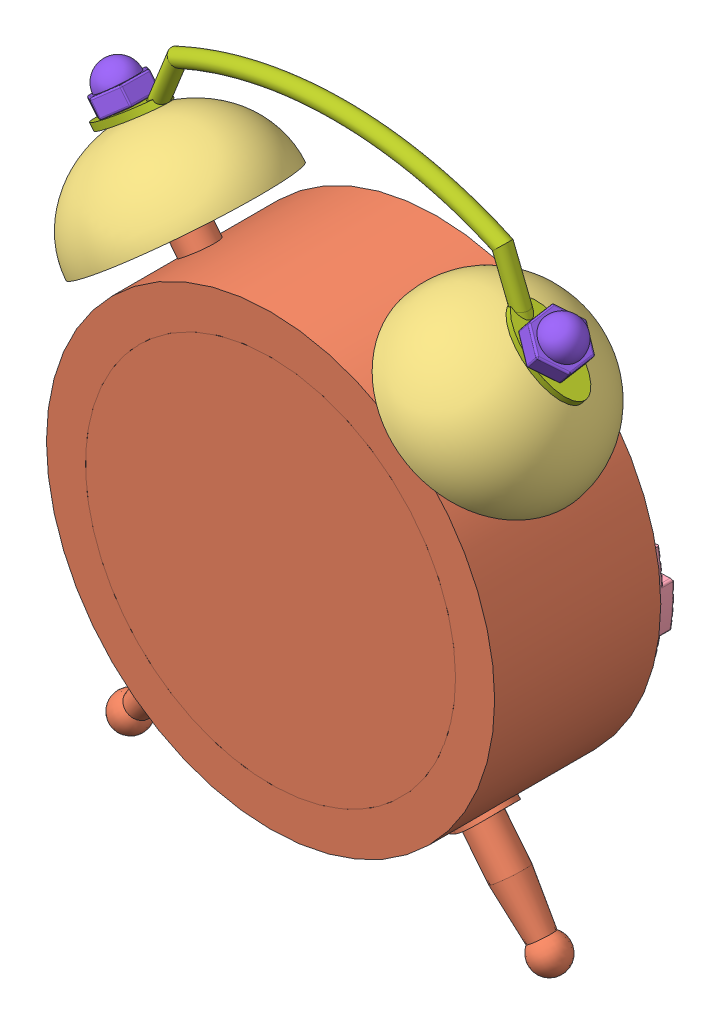
SolidWorks assembly m&m clock assembly, configuration Default. Lengths in mm.
Overall size (94.51 74.03 40.11).
13 component instances, 9 part files, 25 mates.
Components (placement in the parent):
- inner body-1: inner body [Default] at origin size (49.9 49.9 19.3)
- clock casing-2: clock casing [Default] at (0 0 18.3) size (94.51 65.37 40.11)
- bell-1: bell [Default] at (17.3435 21.8712 10.4494) x (0.780381 -0.625305 0) z (0 0 1) size (21.5 9.58 21.5)
- bell-2: bell [Default] at (-17.5711 21.6888 10.4) x (0.780381 0.625305 0) z (0 0 1) size (21.5 9.58 21.5)
- alarm switch-2: alarm switch [Default] x (-0.998274 0.058723 0) z (0 0 -1) size (25.97 12.5 2.77)
- battery lid-1: battery lid [Default] at (-6.5 -13.95 1.5) x (-0.971009 0.239044 0) z (-0.239044 -0.971009 0) size (13 3 13)
- dials-1: dials [Default] at (12.533 -11.5461 0) x (0.996737 0.08072 0) z (-0.08072 0.996737 0) size (7.02 1.74 7.02)
- dials-2: dials [Default] at (-11.5 8.45 0) x (1 0 0) z (0 1 0) size (7.02 1.74 7.02)
- bell bar-5: bell bar [Default] at (0.01 32.3835 10.4) x (1 0.00008 0) z (0 0 1) size (56.5 17.19 4.8)
- bell nut-2: bell nut [Default] at (24.0117 29.9666 10.4) x (0.767462 -0.614953 -0.181205) z (0.141409 -0.113308 0.983445) size (5.59 5.44 6.16)
- bell nut-3: bell nut [Default] at (-24.0117 29.9666 10.4) x (0.780381 0.625305 0) z (0 0 1) size (5.59 5.44 6.16)
- screw-2: screw [Default] at (0 22.2891 -0.0044) x (-0.954512 0.298172 0) z (-0.298172 -0.954512 0) size (3 6.5 3)
- screw-3: screw [Default] at (0 -22.2891 -0.1074) x (-0.999748 -0.022436 0) z (0.022436 -0.999748 0) size (3 6.5 3)
Mates (geometry in assembly coordinates):
- Coincident4: coincident anti-aligned: plane of clock face + plastic-1 through (0 0 17.8) normal (0 0 1); plane of main body-2 through (0 0 17.8) normal (0 0 -1)
- Concentric2: concentric aligned: cylinder of clock face + plastic-1 through (0 0 17.8) axis (0 0 -1) radius 24.95; cylinder of main body-2 through (0 0 17.8) axis (0 0 -1) radius 25
- Tangent1: tangent: cylinder of assembly; face of clock casing-2; cylinder of bell-1 through (17.3435 21.8712 10.4494) axis (0.625305 0.780381 0) radius 1.6
- Coincident6: coincident anti-aligned: plane of main body-2 through (23.1363 28.8741 10.4) normal (0.625305 0.780381 0); circle of bell-1
- Tangent2: tangent: cylinder of assembly; face of clock casing-2; cylinder of bell-2 through (-17.5711 21.6888 10.4) axis (-0.625305 0.780381 0) radius 1.6
- Coincident7: coincident anti-aligned: plane of main body-2 through (-23.1363 28.8741 10.4) normal (-0.625305 0.780381 0); circle of bell-2
- Coincident9: coincident anti-aligned: plane of clock face + plastic-1 through (0 0 0) normal (0 0 -1); plane of alarm switch-2 through (0 0 0) normal (0 0 1)
- Concentric7: concentric aligned: cylinder of clock face + plastic-1 through (0 0 -1) axis (0 0 1) radius 0.5; cylinder of alarm switch-2 through (0 0 -1) axis (0 0 1) radius 0.5
- Coincident10: coincident anti-aligned: plane of clock face + plastic-1 through (-6.5 -13.95 1.5) normal (0 0 -1); plane of battery lid-1 through (-6.5 -13.95 1.5) normal (0 0 1)
- Coincident11: coincident aligned: circle of clock face + plastic-1; circle of battery lid-1
- Concentric8: concentric aligned: cylinder of clock face + plastic-1 through (12.533 -11.5461 -1) axis (0 0 1) radius 0.5; cylinder of dials-1 through (12.533 -11.5461 -1) axis (0 0 1) radius 0.5
- Coincident15: coincident aligned: plane of clock face + plastic-1 through (0 0 0) normal (0 0 -1); circle of dials-1
- Concentric9: concentric aligned: cylinder of clock face + plastic-1 through (-11.5 8.45 -1) axis (0 0 1) radius 0.5; cylinder of dials-2 through (-11.5 8.45 -1) axis (0 0 1) radius 0.5
- Coincident16: coincident aligned: plane of clock face + plastic-1 through (0 0 0) normal (0 0 -1); circle of dials-2
- Concentric18: concentric aligned: circle of main body-2; circle of bell bar (1)-5
- Coincident22: coincident aligned: circle of bell-2; plane of bell bar (1)-5 through (-23.4419 29.2554 10.4) normal (0.625305 -0.780381 0)
- Parallel1: parallel: plane of main body-2 through (0 0 10.4) normal (0 0 1); line of bell bar (1)-5 through (-24.755 32.3815 10.4) axis (1 0.00008 0)
- Concentric22: concentric aligned: circle of main body-2; circle of bell nut+bolt-2
- Distance2: distance = 0.1 mm anti-aligned: plane of main body-2 through (26.2628 32.776 10.4) normal (0.625305 0.780381 0); plane of bell nut+bolt-2 through (26.3253 32.854 10.4) normal (-0.625305 -0.780381 0)
- Concentric24: concentric anti-aligned: circle of main body-2; circle of bell nut+bolt-3
- Distance3: distance = 0.1 mm anti-aligned: plane of bell nut+bolt-3 through (-26.3253 32.854 10.4) normal (0.625305 -0.780381 0); plane of main body-2 through (-26.2628 32.776 10.4) normal (-0.625305 0.780381 0)
- Parallel4: parallel: line of main body-2 through (-45.6453 -31.2 10.4) axis (1 0 0)
- Perpendicular2: perpendicular: line of main body-2 through (-45.6453 -31.2 10.4) axis (1 0 0)
- Concentric25: concentric aligned: circle of clock face + plastic-1; circle of screw-2
- Concentric26: concentric aligned: circle of clock face + plastic-1; circle of screw-3
